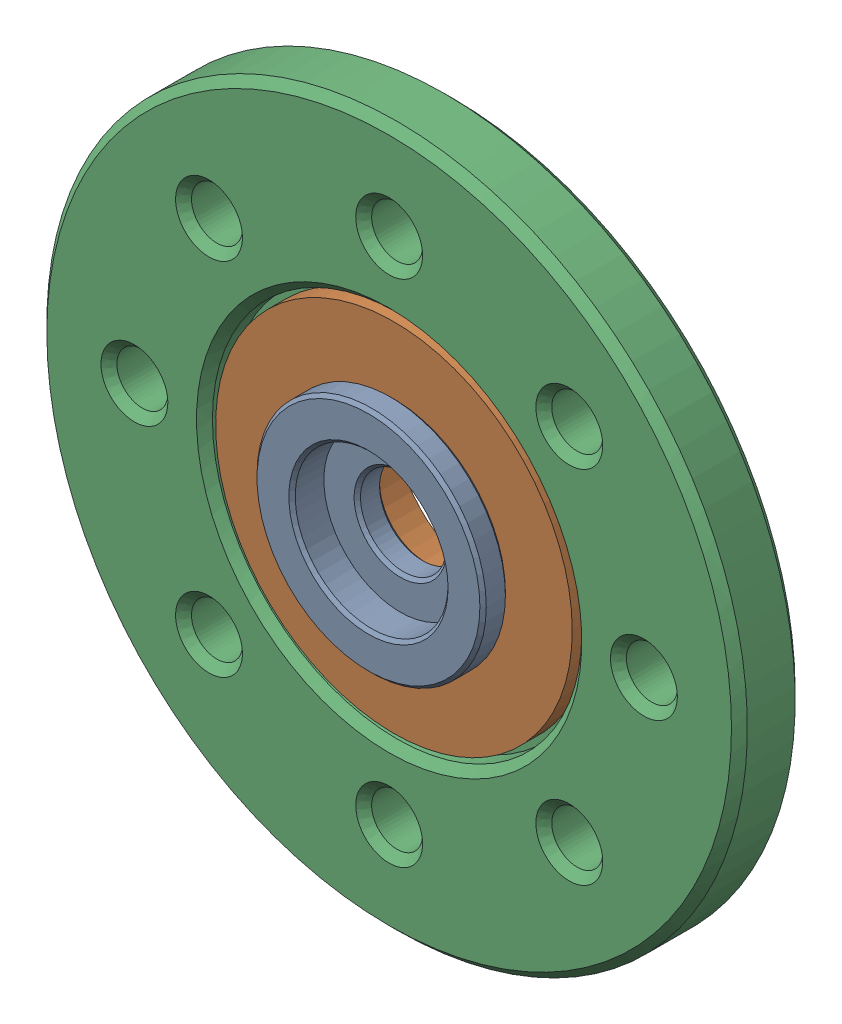
SolidWorks assembly i101_Set(FR07), configuration Default. Lengths in mm.
Overall size (22 22 3.8).
3 component instances, 3 part files, 0 mates.
Components (placement in the parent):
- RX28-CAP-1: RX28-CAP [Default] at (0 0 -0.15) size (7.2 7.2 1.8)
- MF106ZZ-1: MF106ZZ [Default] at (0 0 -0.15) x (-0.837169 0.546944 0) z (-0.546944 -0.837169 0) size (11.2 3 11.2)
- HN07-i101-1: HN07-i101 [Default] x (1 0 0) z (0 -1 0) size (22 3.05 22)
